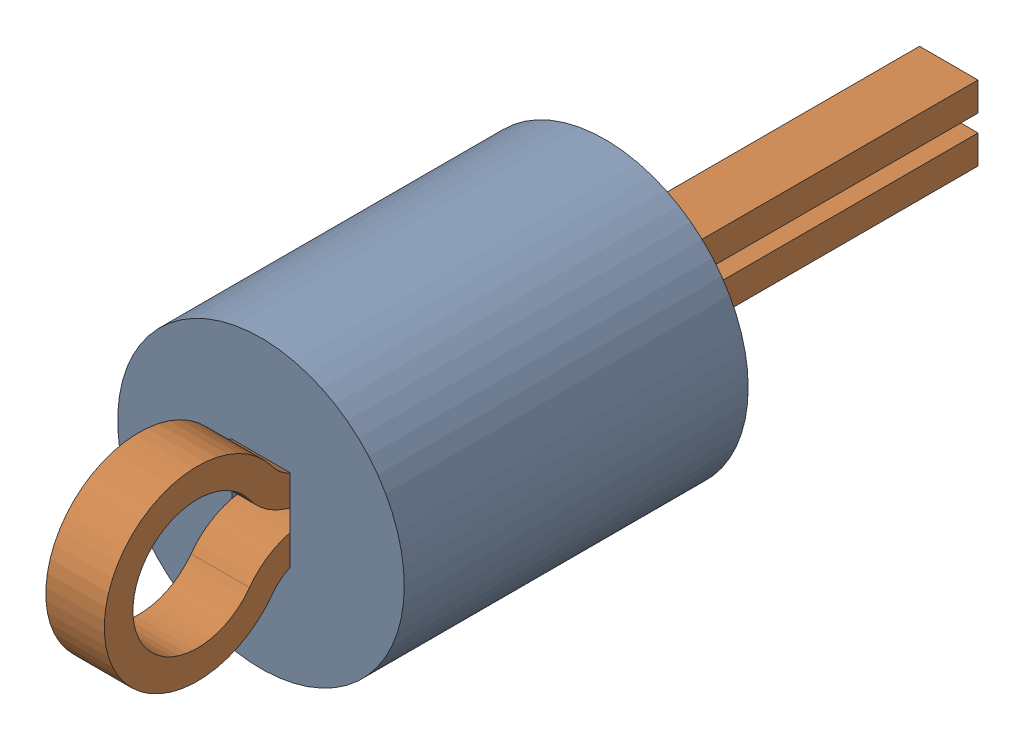
SolidWorks assembly TP3, configuration Default. Lengths in mm.
Overall size (2.5 2.5 7.62).
3 component instances, 2 part files, 0 mates.
Components (placement in the parent):
- Keystone_5002-1: Keystone_5002 [Default] at (12.6955 31.7529 0) size (2.5 2.5 7.62)
  - Keystone5002_white-1: Keystone5002_white [Default] at origin size (2.5 2.5 3)
  - Keystone500x_wire-1: Keystone500x_wire [Default] at origin size (0.51 1.62 7.62)
